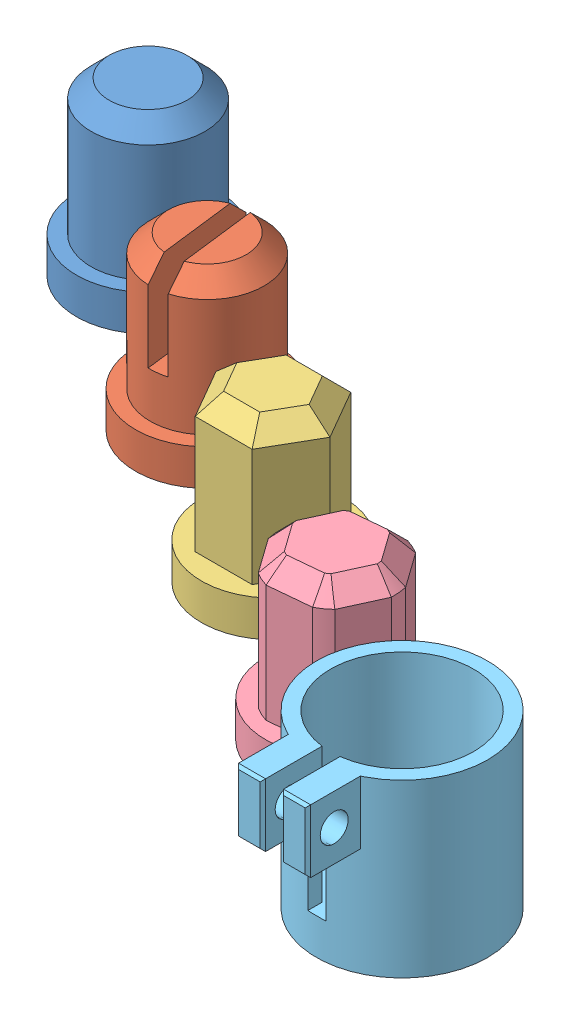
SolidWorks assembly plug-concepts, configuration Default. Lengths in mm.
Overall size (92.15 19.15 68.92).
5 component instances, 5 part files, 7 mates.
Components (placement in the parent):
- cylindrical-plug^plug-concepts-1: cylindrical-plug^plug-concepts [Default] x (1 0 0) z (0 1 0) size (15.88 15.88 19) (virtual)
- cylindrical-plug with slot^plug-concepts-2: cylindrical-plug with slot^plug-concepts [Default] at (18.1218 0 11.5663) x (0.992546 0 -0.121869) z (0 1 0) size (15.88 15.88 19) (virtual)
- hexagonal-plug^plug-concepts-3: hexagonal-plug^plug-concepts [Default] at (36.3014 0 22.4477) x (1 0 0) z (0 1 0) size (15.88 15.88 19) (virtual)
- hybrid-plug^plug-concepts-4: hybrid-plug^plug-concepts [Default] at (55.0841 0 34.1327) x (1 0 0) z (0 1 0) size (15.88 15.88 19) (virtual)
- bracket^plug-concepts-5: bracket^plug-concepts [Default] at (74.7069 -0.1545 46.5292) x (1 0 0) z (0 1 0) size (19 23.95 19) (virtual)
Mates (geometry in assembly coordinates):
- InPlace1: in place: plane of cylindrical-plug^plug-concepts-1 through (0 0 0) normal (0 1 0); moOrthogonalPlaneRef_w of cylindrical-plug^plug-concepts-1 through (0 0 0) normal (0 0 -1); line of cylindrical-plug^plug-concepts-1 through (55 -55 0) axis (0 0 1); unknown of cylindrical-plug^plug-concepts-1
- Coincident1: coincident aligned: plane of cylindrical-plug^plug-concepts-1; plane of assembly
- Coincident2: coincident aligned: plane of cylindrical-plug^plug-concepts-1 through (0 0 0) normal (0 0 -1); moOrthogonalPlaneRef_w of assembly
- Coincident3: coincident anti-aligned: plane of cylindrical-plug^plug-concepts-1; moOrthogonalPlaneRef_w of assembly
- Coincident4: coincident aligned: plane of cylindrical-plug^plug-concepts-1 through (0 0 0) normal (0 -1 0); plane of cylindrical-plug with slot^plug-concepts-2 through (18.1218 0 11.5663) normal (0 -1 0)
- Coincident5: coincident aligned: plane of cylindrical-plug^plug-concepts-1 through (0 0 0) normal (0 -1 0); plane of hexagonal-plug^plug-concepts-3 through (36.3014 0 22.4477) normal (0 -1 0)
- Coincident6: coincident aligned: plane of cylindrical-plug^plug-concepts-1 through (0 0 0) normal (0 -1 0); plane of hybrid-plug^plug-concepts-4 through (55.0841 0 34.1327) normal (0 -1 0)
